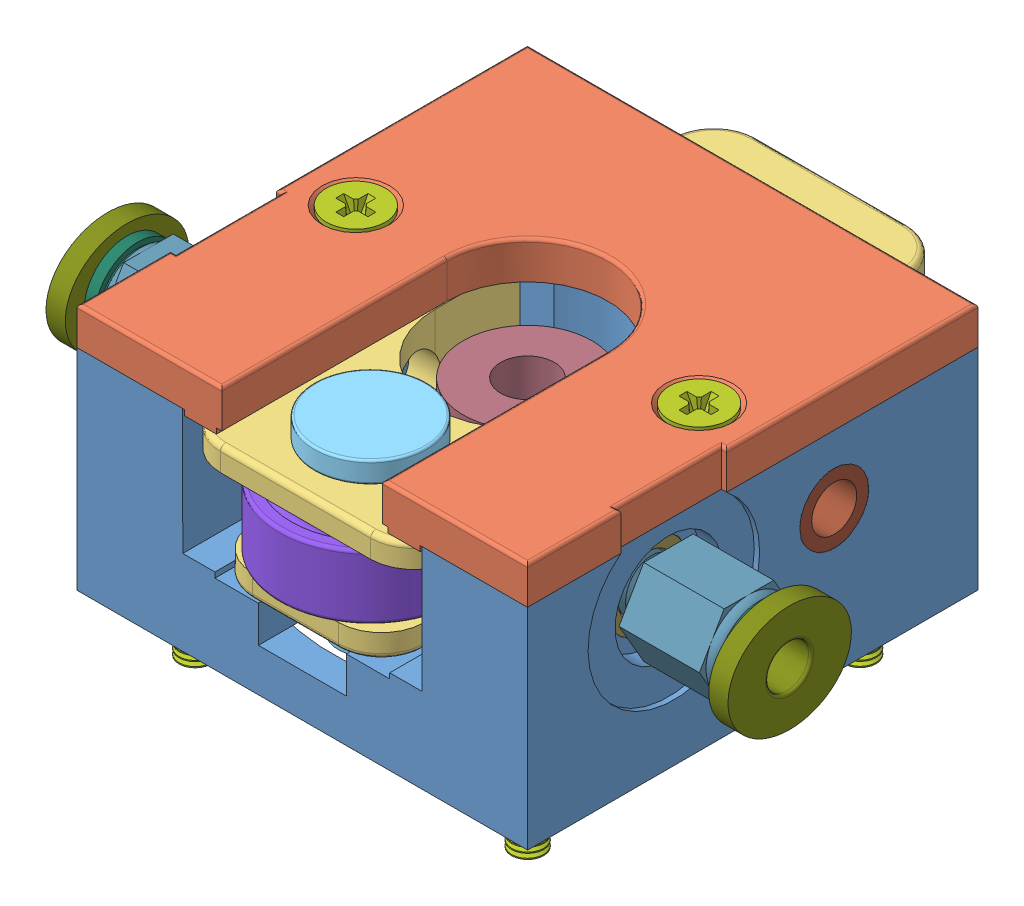
SolidWorks assembly Extrusor, configuration Predeterminado. Lengths in mm.
Overall size (63.61 71.03 52.68).
33 component instances, 18 part files, 56 mates.
Components (placement in the parent):
- Basse-1: Basse [Predeterminado] at (-0.0153 0.0026 -2.9939) x (1 0.000641 0) z (0 0 1) size (42 21.5 42)
- Tapa-1: Tapa [Predeterminado] at (-0.0176 3.5026 -2.9939) x (1 0.000641 0) z (0 0 1) size (42 4 42)
- Empujador-1: Empujador [Predeterminado] at (-0.015 -0.5974 -6.3697) x (-1 -0.000641 0) z (0 0 -1) size (22 11 50)
- Muelle-1: Muelle [Default] at (-3.9239 -5.9972 -23.5215) x (0.99759 0.06938 0.000016) z (0.00304 -0.043937 0.99903) size (6.02 6.09 11.75)
- Muelle-2: Muelle [Default] at (3.4631 -5.9484 -22.8222) x (0.444628 0.895715 0) z (0.039448 -0.019582 0.99903) size (6.02 6.09 11.75)
- Eje Empujador-1: Eje Empujador [Predeterminado] at (-3.0053 -15.5994 11.6303) x (1 0.000641 0) z (0.000641 -1 0) size (10.5 10.5 17.5)
- slotted set screw dog point_jis-1: slotted set screw dog point_jis [JIS B 1117 Long dog point M4 x 12--S] at (-4.0114 -6.1 -32.5466) x (0 0 1) z (0.594696 0.803951 0) size (12 4 4)
- slotted set screw dog point_jis-2: slotted set screw dog point_jis [JIS B 1117 Long dog point M4 x 12--S] at (3.9886 -6.0949 -32.2333) x (0 0 1) z (-0.953222 0.302272 0) size (12 4 4)
- countersunk flat head cross recess screw_iso-1: countersunk flat head cross recess screw_iso [ISO 7046-1 - M3 x 10 - Z --- 10S] at (-16.0176 3.4923 -2.9939) x (0.000641 -1 0) z (0 0 1) size (10 5.5 5.5)
- countersunk flat head cross recess screw_iso-2: countersunk flat head cross recess screw_iso [ISO 7046-1 - M3 x 10 - Z --- 10S] at (15.9824 3.5128 -2.9939) x (0.000641 -1 0) z (0 0 1) size (10 5.5 5.5)
- angular contact ball bearing_68_iso-2: angular contact ball bearing_68_iso [ISO 15 ABB - 106 - 8,SI,NC,8_68] at (-0.0114 -6.0974 11.6303) x (0.000641 -1 0) z (0 0 1) size (6 17 17)
- lock washer for shafts_din-1: lock washer for shafts_din [Lock washer DIN 6799 - 5] at (-0.0079 -11.5974 11.6303) x (1 0.000641 0) z (-0.000641 1 0) size (11.3 9.55 0.7)
- Inserto M3-1: Inserto M3 [Predeterminado] at (-16.0089 -10.0077 -2.9939) x (0.361954 0.000232 0.932196) z (-0.000641 1 0) size (4.5 4.5 10)
- Inserto M3-2: Inserto M3 [Predeterminado] at (15.9911 -9.9872 -2.9939) x (1 0.000641 0) z (-0.000641 1 0) size (4.5 4.5 10)
- Inserto M5-1: Inserto M5 [Predeterminado] at (20.9887 -6.284 -10.5939) x (0 0 1) z (-1 -0.000641 0) size (6.5 6.5 9.85)
- Inserto M5-2: Inserto M5 [Predeterminado] at (-21.0113 -6.3109 -10.5939) x (0 0 -1) z (1 0.000641 0) size (6.5 6.5 9.85)
- Inserto 1_4-28-1: Inserto 1_4-28 [Predeterminado] at (-11.1613 -6.3046 4.3561) x (0 0 1) z (-1 -0.000641 0) size (7.7 7.7 7.35)
- Inserto 1_4-28-2: Inserto 1_4-28 [Predeterminado] at (18.4887 -6.2856 4.3561) x (0 0 1) z (-1 -0.000641 0) size (7.7 7.7 7.35)
- Inserto M5-3: Inserto M5 [D8] at (4 -6.1 -31.3697) size (6.5 6.5 8)
- Inserto M5-4: Inserto M5 [D8] at (-4.0114 -6.1 -31.3697) size (6.5 6.5 8)
- nema17-1: nema17 [Défaut] at (-0.0028 -19.5974 -2.9939) x (1 0.000641 0) z (0.000641 -1 0) size (42 42 71) (hidden)
- Rodillo-1: Rodillo [Predeterminado] at (-0.007 -12.9474 -2.9939) x (0.923728 0.000593 0.383049) z (-0.000641 1 0) size (12 12 10.5)
- AW6  Fitting-1: AW6  Fitting [Défaut] at (-14.0113 -6.3064 4.3561) x (0 0 1) z (-1 -0.000641 0) size (9.24 8 15.43)
- Easy realise fitting part1-1: Easy realise fitting part1 [Default] at (-29.0113 -6.316 4.3561) x (0 0 1) z (-0.000641 1 0) size (8 6.5 8)
- Easy realise fitting part2-1: Easy realise fitting part2 [Default] at (-31.8113 -6.3178 4.3561) x (0 0 1) z (-0.000641 1 0) size (11.5 7.3 10)
- AW6  Fitting-2: AW6  Fitting [Défaut] at (13.9887 -6.2885 4.3561) x (0 0 -1) z (1 0.000641 0) size (9.24 8 15.43)
- Easy realise fitting part1-2: Easy realise fitting part1 [Default] at (28.9887 -6.2788 4.3561) x (0 0 -1) z (-0.000641 1 0) size (8 6.5 8)
- Easy realise fitting part2-2: Easy realise fitting part2 [Default] at (31.7887 -6.277 4.3561) x (0 0 -1) z (-0.000641 1 0) size (11.5 7.3 10)
- countersunk flat head cross recess screw_iso-7: countersunk flat head cross recess screw_iso [ISO 7046-1 - M3 x 25 - Z --- 25S] at (-15.5153 -0.0074 -18.4939) x (0.000641 -1 0) z (0 0 1) size (25 5.5 5.5)
- countersunk flat head cross recess screw_iso-8: countersunk flat head cross recess screw_iso [ISO 7046-1 - M3 x 25 - Z --- 25S] at (15.4846 0.0125 -18.4939) x (0.000641 -1 0) z (0 0 1) size (25 5.5 5.5)
- countersunk flat head cross recess screw_iso-9: countersunk flat head cross recess screw_iso [ISO 7046-1 - M3 x 25 - Z --- 25S] at (15.4846 0.0125 12.5061) x (0.000641 -1 0) z (0 0 1) size (25 5.5 5.5)
- countersunk flat head cross recess screw_iso-10: countersunk flat head cross recess screw_iso [ISO 7046-1 - M3 x 25 - Z --- 25S] at (-15.5153 -0.0074 12.5061) x (0.000641 -1 0) z (0 0 1) size (25 5.5 5.5)
- socket set screw cone point_iso-1: socket set screw cone point_iso [ISO 4027 - M3 x 4-N] at (2.239 -10.146 -8.4146) x (-0.383049 -0.000246 0.923728) z (-0.923728 0.000368 -0.383049) size (4 3 3)
Mates (geometry in assembly coordinates):
- Concéntrica1: concentric anti-aligned: cylinder of Basse-1 through (15.9807 6.2354 -2.9939) axis (0.000641 -1 0) radius 2.2; cylinder of Tapa-1 through (15.9824 3.5128 -2.9939) axis (-0.000641 1 0) radius 1.7
- Concéntrica2: concentric anti-aligned: cylinder of Basse-1 through (-16.0193 6.2148 -2.9939) axis (0.000641 -1 0) radius 2.2; cylinder of Tapa-1 through (-16.0176 3.4923 -2.9939) axis (-0.000641 1 0) radius 1.7
- Coincidente1: coincident anti-aligned: plane of Basse-1 through (-0.0153 0.0026 -2.9939) normal (-0.000641 1 0); plane of Tapa-1 through (-0.0153 0.0026 -2.9939) normal (0.000641 -1 0)
- Ancho1: width anti-aligned: plane of Basse-1 through (-11.1578 -11.7046 -23.9939) normal (1 0.000641 0); plane of Empujador-1 through (11.1422 -11.6903 -23.9939) normal (-1 -0.000641 0); plane of Basse-1 through (-11.0079 -11.6045 14.6303) normal (-1 -0.000641 0); plane of Empujador-1 through (10.9921 -11.5904 14.6303) normal (1 0.000641 0)
- Tangente3: tangent aligned: plane of Basse-1 through (3.9886 -6.1949 -12.2939) normal (0 0 -1); face of Muelle-2
- Tangente4: tangent anti-aligned: cylinder of Basse-1 through (3.9886 -6.1949 -12.2939) axis (0 0 -1) radius 2.7; edge_curve of Muelle-2
- Tangente5: tangent anti-aligned: plane of Basse-1 through (-4.0114 -6.2 -12.2939) normal (0 0 -1); edge_curve of Muelle-1
- Tangente6: tangent aligned: cylinder of Basse-1 through (-4.0114 -6.2 -12.2939) axis (0 0 -1) radius 2.7; edge_curve of Muelle-1
- Concéntrica3: concentric aligned: cylinder of Empujador-1 through (-0.015 -0.5974 11.6303) axis (-0.000641 1 0) radius 3; cylinder of Eje Empujador-1 through (-0.0166 1.9026 11.6303) axis (-0.000641 1 0) radius 3
- Concéntrica4: concentric aligned: cylinder of Empujador-1 through (-4.0114 -6.1 -31.3697) axis (0 0 -1) radius 3.2; cylinder of slotted set screw dog point_jis-1 through (-4.0114 -6.1 -45.2466) axis (0 0 -1) radius 2
- Concéntrica5: concentric aligned: cylinder of Empujador-1 through (3.9886 -6.0949 -31.3697) axis (0 0 -1) radius 3.2; cylinder of slotted set screw dog point_jis-2 through (3.9886 -6.0949 -44.9333) axis (0 0 -1) radius 2
- Concéntrica6: concentric anti-aligned: cylinder of Eje Empujador-1 through (-0.0166 1.9026 11.6303) axis (-0.000641 1 0) radius 3; cylinder of ? through (0 14.4375 11.0262) axis (0 -1 0) radius 3
- Ancho2: width anti-aligned: plane of Empujador-1 through (10.9907 -9.3904 19.6936) normal (-0.000641 1 0); plane of Empujador-1 through (10.9864 -2.7904 0.3303) normal (0.000641 -1 0); plane of ? through (6.3362 -9.2 4.3559) normal (0 -1 0); plane of ? through (5.6302 -3.2 5.099) normal (0 1 0)
- Coincidente5: coincident aligned: cone of Tapa-1 through (-16.0176 3.4923 -2.9939) axis (0.000641 -1 0); cone of countersunk flat head cross recess screw_iso-1 through (-16.0173 3.0923 -2.9939) axis (0.000641 -1 0)
- Coincidente6: coincident aligned: cone of Tapa-1 through (15.9824 3.5128 -2.9939) axis (0.000641 -1 0); cone of countersunk flat head cross recess screw_iso-2 through (15.9827 3.1128 -2.9939) axis (0.000641 -1 0)
- Concéntrica7: concentric anti-aligned: cylinder of Eje Empujador-1 through (-0.0166 1.9026 11.6303) axis (-0.000641 1 0) radius 3; cylinder of angular contact ball bearing_68_iso-2 through (-0.0247 14.5401 11.6303) axis (0.000641 -1 0) radius 3
- Ancho3: width anti-aligned: plane of Empujador-1 through (10.9907 -9.3904 19.6936) normal (-0.000641 1 0); plane of Empujador-1 through (10.9864 -2.7904 0.3303) normal (0.000641 -1 0); plane of angular contact ball bearing_68_iso-2 through (8.1905 -9.0922 11.6303) normal (0.000641 -1 0); plane of angular contact ball bearing_68_iso-2 through (7.3616 -3.0927 11.6303) normal (-0.000641 1 0)
- Ancho4: width aligned: plane of Empujador-1 through (6.985 -0.593 -27.3697) normal (-0.000641 1 0); plane of Basse-1 through (6.9921 -11.5929 -27.3697) normal (0.000641 -1 0); plane of Empujador-1 through (-0.0078 -11.6974 -2.9939) normal (-0.000641 1 0); plane of Tapa-1 through (-0.015 -0.4974 -2.9939) normal (0.000641 -1 0)
- Concéntrica8: concentric aligned: cylinder of Eje Empujador-1 through (-0.0166 1.9026 11.6303) axis (-0.000641 1 0) radius 2.5; cylinder of lock washer for shafts_din-1 through (-0.0075 -12.2974 11.6303) axis (-0.000641 1 0) radius 2.5
- Coincidente7: coincident anti-aligned: plane of Eje Empujador-1 through (-3.0079 -11.5994 11.6303) normal (0.000641 -1 0); plane of lock washer for shafts_din-1 through (-0.0079 -11.5974 11.6303) normal (-0.000641 1 0)
- Concéntrica9: concentric anti-aligned: cylinder of Basse-1 through (-16.0193 6.2148 -2.9939) axis (0.000641 -1 0) radius 2.2; cylinder of Inserto M3-1 through (-16.0153 -0.0077 -2.9939) axis (-0.000641 1 0) radius 1.25
- Coincidente8: coincident aligned: plane of Basse-1 through (-0.0153 0.0026 -2.9939) normal (-0.000641 1 0); plane of Inserto M3-1 through (-16.0153 -0.0077 -2.9939) normal (-0.000641 1 0)
- Concéntrica10: concentric anti-aligned: cylinder of Basse-1 through (15.9807 6.2354 -2.9939) axis (0.000641 -1 0) radius 2.2; cylinder of Inserto M3-2 through (15.9846 0.0128 -2.9939) axis (-0.000641 1 0) radius 1.25
- Coincidente9: coincident aligned: plane of Basse-1 through (-0.0153 0.0026 -2.9939) normal (-0.000641 1 0); plane of Inserto M3-2 through (15.9846 0.0128 -2.9939) normal (-0.000641 1 0)
- Concéntrica11: concentric anti-aligned: cylinder of Basse-1 through (20.9887 -6.284 -10.5939) axis (1 0.000641 0) radius 3.2; cylinder of Inserto M5-1 through (11.1387 -6.2903 -10.5939) axis (-1 -0.000641 0) radius 2.1
- Coincidente10: coincident aligned: plane of Basse-1 through (20.9972 -19.584 -23.9939) normal (1 0.000641 0); plane of Inserto M5-1 through (20.9887 -6.284 -10.5939) normal (1 0.000641 0)
- Concéntrica12: concentric anti-aligned: cylinder of Basse-1 through (-21.0113 -6.3109 -10.5939) axis (-1 -0.000641 0) radius 3.2; cylinder of Inserto M5-2 through (-11.1613 -6.3046 -10.5939) axis (1 0.000641 0) radius 2.1
- Coincidente11: coincident aligned: plane of Basse-1 through (-21.0028 -19.6109 -23.9939) normal (-1 -0.000641 0); plane of Inserto M5-2 through (-21.0113 -6.3109 -10.5939) normal (-1 -0.000641 0)
- Concéntrica13: concentric anti-aligned: cylinder of Basse-1 through (18.4887 -6.2856 4.3561) axis (1 0.000641 0) radius 3.8; cylinder of Inserto 1_4-28-1 through (-18.5113 -6.3093 4.3561) axis (-1 -0.000641 0) radius 2.7051
- Coincidente12: coincident aligned: plane of Basse-1 through (-18.5113 -6.3093 4.3561) normal (-1 -0.000641 0); plane of Inserto 1_4-28-1 through (-18.5113 -6.3093 4.3561) normal (-1 -0.000641 0)
- Concéntrica14: concentric anti-aligned: cylinder of Basse-1 through (18.4887 -6.2856 4.3561) axis (1 0.000641 0) radius 3.8; cylinder of Inserto 1_4-28-2 through (11.1387 -6.2903 4.3561) axis (-1 -0.000641 0) radius 2.7051
- Coincidente13: coincident aligned: plane of Basse-1 through (18.4887 -6.2856 4.3561) normal (1 0.000641 0); plane of Inserto 1_4-28-2 through (18.4887 -6.2856 4.3561) normal (1 0.000641 0)
- Concéntrica16: concentric anti-aligned: cylinder of Empujador-1 through (-4.0114 -6.1 -31.3697) axis (0 0 -1) radius 3.2; cylinder of Inserto M5-4 through (-4.0114 -6.1 -23.3697) axis (0 0 1) radius 2.1
- Coincidente15: coincident aligned: plane of Empujador-1 through (6.9921 -11.5929 -31.3697) normal (0 0 -1); plane of Inserto M5-4 through (-4.0114 -6.1 -31.3697) normal (0 0 -1)
- Coincidente16: coincident aligned: plane of Empujador-1 through (6.9921 -11.5929 -27.3697) normal (0.000641 -1 0); plane of Eje Empujador-1 through (-3.0079 -11.5994 11.6303) normal (0.000641 -1 0)
- Coincidente18: coincident anti-aligned: plane of Basse-1 through (-0.0028 -19.5974 -2.9939) normal (0.000641 -1 0); plane of nema17-1 through (-0.0028 -19.5974 -2.9939) normal (-0.000641 1 0)
- Concéntrica18: concentric aligned: cylinder of Basse-1 through (-0.0053 -15.5974 -2.9939) axis (0.000641 -1 0) radius 18.25; cylinder of nema17-1 through (-0.0041 -17.5974 -2.9939) axis (0.000641 -1 0) radius 11
- Concéntrica19: concentric aligned: cylinder of nema17-1 through (-0.0182 4.4026 -2.9939) axis (0.000641 -1 0) radius 2.5; cylinder of Rodillo-1 through (-0.0138 -2.4474 -2.9939) axis (0.000641 -1 0) radius 2.5
- Ancho5: width anti-aligned: plane of Rodillo-1 through (5.5317 -7.3439 -0.6956) normal (-0.000641 1 0); plane of Rodillo-1 through (5.2992 -4.844 -0.7914) normal (0.000641 -1 0); plane of angular contact ball bearing_68_iso-2 through (8.1905 -9.0922 11.6303) normal (0.000641 -1 0); plane of angular contact ball bearing_68_iso-2 through (7.3616 -3.0927 11.6303) normal (-0.000641 1 0)
- Concéntrica20: concentric aligned: cylinder of AW6  Fitting-1 through (-24.0113 -6.3128 4.3561) axis (-1 -0.000641 0) radius 3; cylinder of Easy realise fitting part1-1 through (-23.5113 -6.3125 4.3561) axis (-1 -0.000641 0) radius 3.5
- Coincidente19: coincident anti-aligned: circle of AW6  Fitting-1; plane of Easy realise fitting part1-1 through (-29.0113 -6.316 4.3561) normal (1 0.000641 0)
- Concéntrica21: concentric anti-aligned: cylinder of Easy realise fitting part1-1 through (-30.0113 -6.3167 4.3561) axis (1 0.000641 0) radius 2.75; cylinder of Easy realise fitting part2-1 through (-24.5113 -6.3132 4.3561) axis (-1 -0.000641 0) radius 2.75
- Coincidente20: coincident anti-aligned: plane of Easy realise fitting part1-1 through (-30.0113 -6.3167 4.3561) normal (-1 -0.000641 0); plane of Easy realise fitting part2-1 through (-30.0113 -6.3167 4.3561) normal (1 0.000641 0)
- Coincidente21: coincident anti-aligned: plane of Basse-1 through (-20.5113 -6.3106 4.3561) normal (-1 -0.000641 0); plane of AW6  Fitting-1 through (-20.5113 -6.3106 4.3561) normal (1 0.000641 0)
- Concéntrica23: concentric anti-aligned: cylinder of Inserto 1_4-28-1 through (-18.5113 -6.3093 4.3561) axis (-1 -0.000641 0) radius 2.7051; cylinder of Easy realise fitting part2-1 through (-31.8113 -6.3178 4.3561) axis (1 0.000641 0) radius 2
- Concéntrica24: concentric aligned: cylinder of AW6  Fitting-2 through (23.9887 -6.282 4.3561) axis (1 0.000641 0) radius 3; cylinder of Easy realise fitting part1-2 through (23.4887 -6.2824 4.3561) axis (1 0.000641 0) radius 3.5
- Coincidente22: coincident anti-aligned: circle of AW6  Fitting-2; plane of Easy realise fitting part1-2 through (28.9887 -6.2788 4.3561) normal (-1 -0.000641 0)
- Concéntrica25: concentric anti-aligned: cylinder of Easy realise fitting part1-2 through (29.9887 -6.2782 4.3561) axis (-1 -0.000641 0) radius 2.75; cylinder of Easy realise fitting part2-2 through (24.4887 -6.2817 4.3561) axis (1 0.000641 0) radius 2.75
- Coincidente23: coincident anti-aligned: plane of Easy realise fitting part1-2 through (29.9887 -6.2782 4.3561) normal (1 0.000641 0); plane of Easy realise fitting part2-2 through (29.9887 -6.2782 4.3561) normal (-1 -0.000641 0)
- Coincidente24: coincident anti-aligned: plane of Basse-1 through (20.4887 -6.2843 4.3561) normal (1 0.000641 0); plane of AW6  Fitting-2 through (20.4887 -6.2843 4.3561) normal (-1 -0.000641 0)
- Concéntrica26: concentric aligned: cylinder of Inserto 1_4-28-2 through (11.1387 -6.2903 4.3561) axis (-1 -0.000641 0) radius 2.7051; cylinder of Easy realise fitting part2-2 through (31.7887 -6.277 4.3561) axis (-1 -0.000641 0) radius 2
- Coincidente29: coincident aligned: cone of Basse-1 through (-15.5153 -0.0074 -18.4939) axis (0.000641 -1 0); cone of countersunk flat head cross recess screw_iso-7 through (-15.5151 -0.4074 -18.4939) axis (0.000641 -1 0)
- Coincidente30: coincident aligned: cone of Basse-1 through (15.4846 0.0125 -18.4939) axis (0.000641 -1 0); cone of countersunk flat head cross recess screw_iso-8 through (15.4849 -0.3875 -18.4939) axis (0.000641 -1 0)
- Coincidente31: coincident aligned: cone of Basse-1 through (15.4846 0.0125 12.5061) axis (0.000641 -1 0); cone of countersunk flat head cross recess screw_iso-9 through (15.4849 -0.3875 12.5061) axis (0.000641 -1 0)
- Coincidente32: coincident aligned: cone of Basse-1 through (-15.5153 -0.0074 12.5061) axis (0.000641 -1 0); cone of countersunk flat head cross recess screw_iso-10 through (-15.5151 -0.4074 12.5061) axis (0.000641 -1 0)
- Concéntrica281: concentric aligned: cylinder of Rodillo-1 through (2.2895 -10.146 -8.5363) axis (0.383049 0.000246 -0.923728) radius 1.25; cylinder of socket set screw cone point_iso-1 through (7.1037 -10.1429 -20.146) axis (0.383049 0.000246 -0.923728) radius 1.5
